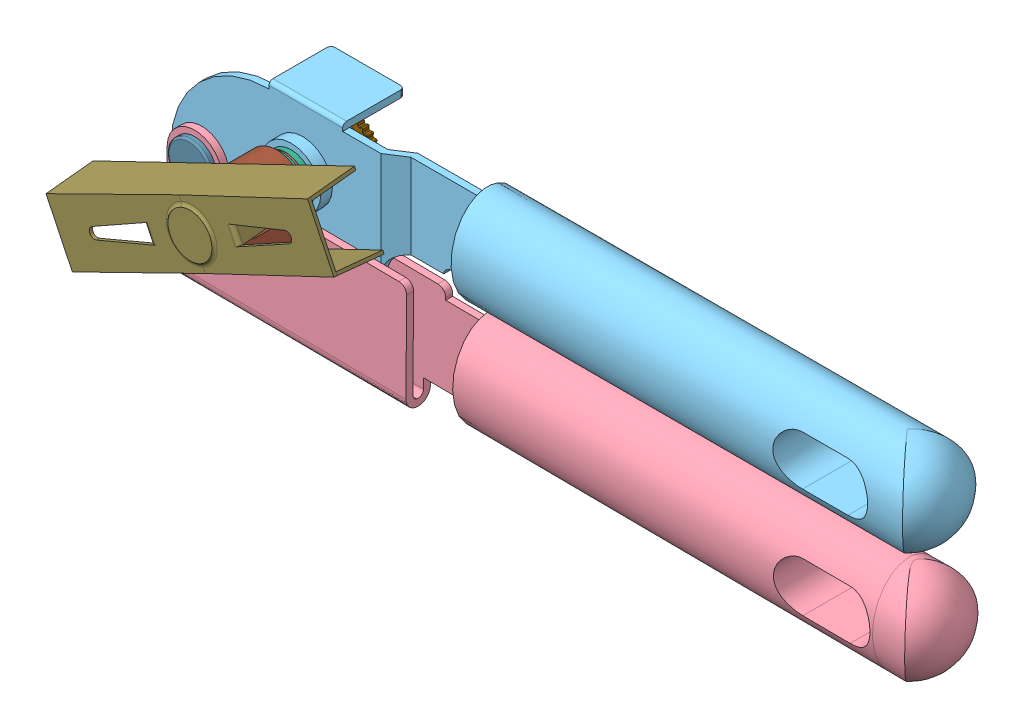
SolidWorks assembly R.E. Assem, configuration Default. Lengths in mm.
Overall size (200.72 63.4 47.7).
15 component instances, 15 part files, 37 mates.
Components (placement in the parent):
- R.E.(blade,gear CONECTION)-1: R.E.(blade,gear CONECTION) [Default] at (-45.1688 -32.3322 -11.6717) x (-0.922111 0.377788 0.083593) z (-0.386922 -0.899389 -0.203445) size (12.07 7.81 12.07)
- R.E.(CIRCLE BLADE)-1: R.E.(CIRCLE BLADE) [Default] at (-45.164 -31.7021 -14.4665) x (0.393712 0.896579 0.202823) z (-0.919232 0.38441 0.085091) size (19.84 1.92 19.84)
- R.E. (Blade Gear)-2: R.E. (Blade Gear) [Default] at (-45.1754 -33.1911 -7.8623) x (0.922111 -0.377788 -0.083593) z (0.386922 0.899389 0.203445) size (19.76 3.15 19.76)
- R.E.(TOP HANDLE)-1: R.E.(TOP HANDLE) [Default] at (-75.9991 -53.5152 -2.532) x (0.999971 -0.007621 0) z (0.007621 0.999971 0) size (196.13 22.72 35.2)
- bot handle 2-1: bot handle 2 [Default] at (0 -11.67 -3.885) x (0 0 -1) z (-1 0 0) size (21.69 45.84 196.03)
- R.E. (Bottom handle mount)-1: R.E. (Bottom handle mount) [Default] at (-43.2271 -15.54 -5.97) x (-0.980159 0.198213 0) z (0 0 1) size (15.48 15.48 14.45)
- R.E. (Gear with square)-1: R.E. (Gear with square) [Default] at (-43.1364 -15.3892 -5.97) x (-0.975668 -0.219255 0) z (0.219255 -0.975668 0) size (19.76 3.15 19.76)
- R.E (Ring with square)-1: R.E (Ring with square) [Default] at (-43.1364 -15.3892 -7.97) x (-0.975668 -0.219255 0) z (0.219255 -0.975668 0) size (13.18 1.77 13.18)
- R.E. ( gear with rod) -1: R.E. ( gear with rod)  [Default] at (-43.2271 -15.54 -11.49) x (-0.975668 -0.219255 0) z (0 0 1) size (17.81 17.81 34.11)
- R.E. (Plastic Rod)-1: R.E. (Plastic Rod) [Default] at (-43.2271 -15.54 -5.97) x (-0.975668 -0.219255 0) z (0 0 1) size (9.14 9.14 30)
- R.E. (SQUARE)-1: R.E. (SQUARE) [Default] at (-43.2271 -15.54 15.73) x (0.900597 0.434655 0) z (0 0 -1) size (23.17 15.75 20.72)
- R.E. (Lever)-1: R.E. (Lever) [Default] at (-43.2461 -15.5007 16.305) x (0.900597 0.434655 0) z (0.434655 -0.900597 -0.000012) size (73.97 17.07 17.35)
- R.E. SPRING-2: R.E. SPRING [Default] at (-43.1733 -15.5533 11.33) x (0.901286 0.433225 0) z (-0.433225 0.901286 0) size (12.78 8.45 12.9)
- R.E. (RIVET)-1: R.E. (RIVET) [Default] at (-68.7844 -25.37 3.378) x (-0.580113 -0.814536 0) z (0 0 -1) size (11.12 11.12 10.87)
- 92467A485_18-8 Stainless Steel Extra-Wide Truss Head Phillips Screws-1: 92467A485_18-8 Stainless Steel Extra-Wide Truss Head Phillips Screws [92467A485] at (-45.1939 -35.6225 2.9219) x (-0.914096 0.395902 0.087691) z (0.001676 0.219943 -0.975511) size (10 10 6.69)
Mates (geometry in assembly coordinates):
- Concentric1: concentric aligned: circle of R.E.(blade,gear CONECTION)-1; circle of R.E.(CIRCLE BLADE)-1
- Coincident4: coincident anti-aligned: plane of R.E.(blade,gear CONECTION)-1 through (-45.1656 -31.9132 -13.5301) normal (0.001676 0.219943 -0.975511); plane of R.E.(CIRCLE BLADE)-1 through (-45.1656 -31.9132 -13.5301) normal (-0.001676 -0.219943 0.975511)
- Coincident11: coincident anti-aligned: plane of bot handle 2-1 through (-23.2973 51.7637 -1.77) normal (0 0 -1); plane of R.E. (Bottom handle mount)-1 through (-43.2271 -15.54 -1.77) normal (0 0 1)
- Coincident15: coincident anti-aligned: plane of R.E (Ring with square)-1 through (-43.1364 -15.3892 -9.74) normal (0 0 -1); plane of R.E. ( gear with rod) -1 through (-43.2271 -15.54 -9.74) normal (0 0 1)
- Coincident16: coincident anti-aligned: plane of R.E (Ring with square)-1 through (-45.1317 -12.7657 -9.74) normal (0.975668 0.219255 0); plane of R.E. ( gear with rod) -1 through (-43.8174 -18.6142 62.7708) normal (-0.975668 -0.219255 0)
- Coincident18: coincident anti-aligned: plane of R.E (Ring with square)-1 through (-41.141 -18.0128 -9.74) normal (-0.219255 0.975668 0); plane of R.E. ( gear with rod) -1 through (-41.3783 -18.0661 62.7708) normal (0.219255 -0.975668 0)
- Coincident19: coincident anti-aligned: plane of R.E. (Gear with square)-1 through (-43.1364 -15.3892 -7.97) normal (0 0 -1); plane of R.E (Ring with square)-1 through (-43.1364 -15.3892 -7.97) normal (0 0 1)
- Coincident20: coincident anti-aligned: plane of R.E. (Gear with square)-1 through (-45.1317 -12.7657 2.03) normal (0.975668 0.219255 0); plane of R.E. ( gear with rod) -1 through (-43.8174 -18.6142 62.7708) normal (-0.975668 -0.219255 0)
- Coincident21: coincident anti-aligned: plane of R.E. (Gear with square)-1 through (-41.141 -18.0128 2.03) normal (-0.219255 0.975668 0); plane of R.E. ( gear with rod) -1 through (-41.3783 -18.0661 62.7708) normal (0.219255 -0.975668 0)
- Coincident27: coincident anti-aligned: plane of R.E. ( gear with rod) -1 through (-42.6368 -12.4658 62.7708) normal (-0.219255 0.975668 0); plane of R.E. (Plastic Rod)-1 through (-42.6368 -12.4658 -5.97) normal (0.219255 -0.975668 0)
- Coincident29: coincident anti-aligned: plane of R.E. (Gear with square)-1 through (-43.1364 -15.3892 -5.97) normal (0 0 1); plane of R.E. (Plastic Rod)-1 through (-43.2271 -15.54 -5.97) normal (0 0 -1)
- Coincident34: coincident anti-aligned: plane of R.E. ( gear with rod) -1 through (-43.8174 -18.6142 62.7708) normal (-0.975668 -0.219255 0); plane of R.E. (Plastic Rod)-1 through (-43.8174 -18.6142 -5.97) normal (0.975668 0.219255 0)
- Distance3: distance = 0.762 mm anti-aligned: plane of R.E.(TOP HANDLE)-1 through (107.7701 -39.2302 -2.532) normal (0 0 1); plane of bot handle 2-1 through (-23.2973 51.7637 -1.77) normal (0 0 -1)
- Concentric12: concentric anti-aligned: cylinder of R.E.(blade,gear CONECTION)-1 through (-45.1754 -33.1911 -7.8623) axis (0.001676 0.219943 -0.975511) radius 3.5306; cylinder of R.E.(TOP HANDLE)-1 through (-45.1621 -31.4469 -15.5981) axis (-0.001676 -0.219943 0.975511) radius 3.02
- Lock2: lock: unknown of R.E. (square)-1; unknown of R.E. (Lever)-1
- Coincident87: coincident anti-aligned: plane of R.E. (square)-1 through (-43.2271 -15.54 11.33) normal (0 0 -1); plane of R.E. SPRING-2 through (-46.1628 -23.8819 11.33) normal (0 0 1)
- Lock3: lock: unknown of R.E. (square)-1; unknown of R.E. SPRING-2
- Coincident90: coincident anti-aligned: plane of R.E. (Plastic Rod)-1 through (-45.7156 -19.2893 65.1318) normal (-0.975668 -0.219255 0); plane of R.E. (square)-1 through (-45.7156 -19.2893 65.1318) normal (0.975668 0.219255 0)
- Tangent10: tangent aligned: cylinder of R.E. (Plastic Rod)-1 through (-43.2271 -15.54 65.1318) axis (0 0 -1) radius 4.5; cylinder of R.E. (square)-1 through (-43.2271 -15.54 65.1318) axis (0 0 -1) radius 4.5
- Coincident93: coincident anti-aligned: plane of R.E.(TOP HANDLE)-1 through (107.7701 -39.2302 1.938) normal (0 0 1); plane of R.E.(RIVET)-1 through (-68.7844 -25.37 1.938) normal (0 0 -1)
- Concentric14: concentric anti-aligned: circle of R.E.(blade,gear CONECTION)-1; circle of 92467A485_18-8 Stainless Steel Extra-Wide Truss Head Phillips Screws-1
- Coincident97: coincident anti-aligned: plane of R.E.(blade,gear CONECTION)-1 through (-45.1754 -33.1911 -7.8623) normal (-0.001676 -0.219943 0.975511); plane of R.E.(TOP HANDLE)-1 through (-45.1754 -33.1911 -7.8623) normal (0.001676 0.219943 -0.975511)
- Coincident98: coincident anti-aligned: plane of R.E.(TOP HANDLE)-1 through (-75.9695 -49.6328 -19.7513) normal (0.001676 0.219943 -0.975511); plane of 92467A485_18-8 Stainless Steel Extra-Wide Truss Head Phillips Screws-1 through (-46.7841 -35.0132 -16.405) normal (-0.001676 -0.219943 0.975511)
- Coincident99: coincident anti-aligned: plane of R.E.(TOP HANDLE)-1 through (107.7701 -39.2302 1.938) normal (0 0 1); plane of R.E.(RIVET)-1 through (-68.7844 -25.37 1.938) normal (0 0 -1)
- Concentric16: concentric anti-aligned: cylinder of R.E.(TOP HANDLE)-1 through (-68.7844 -25.37 5.698) axis (0 0 -1) radius 2.8067; cylinder of R.E.(RIVET)-1 through (-68.7844 -25.37 -25.9705) axis (0 0 1) radius 2.69
- Concentric18: concentric anti-aligned: cylinder of bot handle 2-1 through (-68.7844 -25.37 23.93) axis (0 0 -1) radius 3.302; cylinder of R.E.(RIVET)-1 through (-68.7844 -25.37 -25.9705) axis (0 0 1) radius 2.69
- GearMate1: gear = 13.18 : 12.07 mm: circle of R.E.(blade,gear CONECTION)-1; circle of R.E (Ring with square)-1
- Concentric19: concentric aligned: cylinder of R.E.(blade,gear CONECTION)-1 through (-45.1754 -33.1911 -7.8623) axis (0.001676 0.219943 -0.975511) radius 4.7752; cylinder of R.E. (Blade Gear)-2 through (-45.1761 -33.29 -7.4234) axis (0.001676 0.219943 -0.975511) radius 4.9
- Parallel1: parallel aligned: line of R.E.(blade,gear CONECTION)-1 through (-40.4664 -31.9605 -9.627) axis (-0.386922 -0.899389 -0.203445); line of R.E. (Blade Gear)-2 through (-40.3434 -31.9399 -9.6221) axis (-0.386922 -0.899389 -0.203445)
- Coincident102: coincident anti-aligned: plane of R.E.(blade,gear CONECTION)-1 through (-45.172 -32.7512 -9.8134) normal (-0.001676 -0.219943 0.975511); plane of R.E. (Blade Gear)-2 through (-45.172 -32.7512 -9.8134) normal (0.001676 0.219943 -0.975511)
- Coincident105: coincident aligned: plane of bot handle 2-1 through (-23.2973 51.7637 0) normal (0 0 1)
- Coincident106: coincident aligned: plane of bot handle 2-1 through (0 0 -3.885) normal (0 1 0)
- Concentric22: concentric anti-aligned: cylinder of R.E. (Bottom handle mount)-1 through (-43.2271 -15.54 -5.97) axis (0 0 1) radius 5.08; cylinder of R.E. (Plastic Rod)-1 through (-43.2271 -15.54 11.33) axis (0 0 -1) radius 4.57
- Concentric23: concentric aligned: cylinder of bot handle 2-1 through (-43.2271 -15.54 29.0412) axis (0 0 -1) radius 6.11; cylinder of R.E. (Bottom handle mount)-1 through (-43.2271 -15.54 40.0284) axis (0 0 -1) radius 6.0452
- Coincident109: coincident anti-aligned: plane of bot handle 2-1 through (0 -11.67 -3.885) normal (-1 0 0)
- Coincident110: coincident anti-aligned: plane of R.E. (Plastic Rod)-1 through (-43.2271 -15.54 24.03) normal (0 0 1); plane of R.E. (square)-1 through (-43.2271 -15.54 24.03) normal (0 0 -1)
- Coincident114: coincident anti-aligned: plane of R.E. (Bottom handle mount)-1 through (-43.2271 -15.54 -5.97) normal (0 0 -1); plane of R.E. (Gear with square)-1 through (-43.1364 -15.3892 -5.97) normal (0 0 1)
